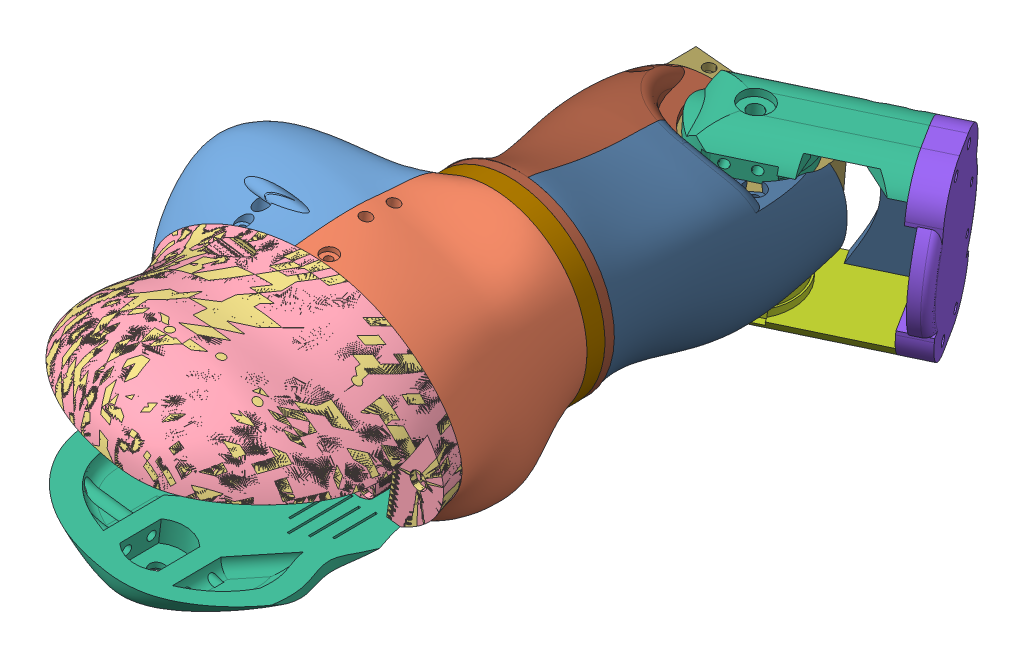
SolidWorks assembly Arm assm L, configuration Default. Lengths in mm.
Overall size (230.27 146.6 398.62).
46 component instances, 28 part files, 28 mates.
Components (placement in the parent):
- middle back L-1: middle back L [Default] at (-34.512 -4.9799 -51.8822) x (0.000653 0.010182 -0.999948) z (-0.991812 0.127707 0.000653) size (90.34 121.18 102.39)
- middle front L-1: middle front L [Default] at (-8.2171 -35.7655 -34.8122) x (0.991812 -0.127707 -0.000653) z (0.000653 0.010182 -0.999948) size (140.79 123.83 87.16)
- top left L-1: top left L [Default] at (-11.5779 -3.0702 -34.4815) x (-0.991812 0.127707 0.000653) z (-0.000653 -0.010182 0.999948) size (182.35 104.85 120.87)
- top brace L-1: top brace L [Default] at (-4.1905 -4.9659 57.5088) x (-0.991812 0.127707 0.000653) z (0.127707 0.99176 0.010182) size (182.35 135.45 104.85)
- left glue widget L-1: left glue widget L [Default] at (-22.5419 19.9221 -28.4086) x (0.000653 0.010182 -0.999948) z (-0.127707 -0.99176 -0.010182) size (13 9 6)
- top right L-1: top right L [Default] at (-10.7036 -55.5456 56.9895) x (-0.000653 -0.010182 0.999948) z (-0.127707 -0.99176 -0.010182) size (132 144.11 34.63)
- gearbox screw block 2 L-1: gearbox screw block 2 L [Default] at (-19.3394 -81.2007 -73.094) x (-0.991625 0.129152 0.000668) z (0.129152 0.991572 0.010181) size (26 29.8 14.3)
- gearbox screw block 1 L-1: gearbox screw block 1 L [Default] at (-25.1738 16.2638 -72.07) x (-0.991625 0.129152 0.000668) z (-0.129152 -0.991572 -0.010181) size (10 29.5 20)
- arm rot mount L-1: arm rot mount L [Default] at (-7.003 -25.9074 -124.2157) x (0.996634 -0.081977 -0.000184) z (-0.000653 -0.010182 0.999948) size (66 66 31)
- lower arm assm L-1: lower arm assm L [Default-_flexible1] at (-87.7884 -5.6779 -95.3829) x (-0.975088 -0.221816 -0.00126) z (0.001292 -0.000001 -0.999999) size (140.99 140.61 148.59) (flexible)
  - arm lower bottom L-1: arm lower bottom L [Default] at (-74.4796 -36.9206 33.9299) x (-0.948607 -0.316453 0.001636) z (-0.001636 0.010071 0.999948) size (61.83 109.64 120.63)
  - arm lower top L-1: arm lower top L [Default] at (-74.4796 -36.9206 33.9299) x (-0.948607 -0.316453 0.001636) z (-0.001636 0.010071 0.999948) size (102.83 109.64 125.02)
  - Mirrorgearbox1-1: Mirrorgearbox1 [Default] at (-78.0538 -48.6826 38.5385) x (0.948607 0.316453 -0.001636) z (0.001636 -0.010071 -0.999948) size (90.22 74 134.56)
    - Mirrorservo gearbox-1: Mirrorservo gearbox [Default] at (7.4002 -24.2748 -89.7718) x (1 0 0) z (0 -1 0) size (87.5 78 20)
    - wormscrew-1: wormscrew [Default] at (21.4002 -4.2748 -75.7718) x (-0.47589 -0.879505 0) z (0 0 -1) size (40 40 51)
    - driveshaft cog-1: driveshaft cog [Default] at (-6.5998 -9.2748 -103.2718) x (0.623441 0 -0.78187) z (0 1 0) size (49.29 49.31 47)
    - Mirrorgearbox top-1: Mirrorgearbox top [Default] at (-6.5998 15.7252 -103.2718) x (-1 0 0) z (0 1 0) size (87.5 78 40)
    - HS-805BB-1: HS-805BB [Default] at (2.9002 -19.2748 -28.6693) x (1 0 0) z (0 1 0) size (83 68.8 30)
    - 608ZZ-1: 608ZZ [Default] at (21.4002 -4.2748 -127.5718) x (0.996867 0.079098 0) z (0 0 1) size (22 22 7)
    - 6806 30x42x7-1: 6806 30x42x7 [Default] at (-6.5998 -22.2748 -103.2718) x (0.979879 0 -0.199591) z (0 1 0) size (42 42 7)
    - 6806 30x42x7-2: 6806 30x42x7 [Default] at (-6.5998 9.7252 -103.2718) x (0.968497 0 -0.249026) z (0 -1 0) size (42 42 7)
    - Mirrorbottom plate pot holder-1: Mirrorbottom plate pot holder [Default] at (-6.5998 15.7252 -103.2718) x (0 0 1) z (0 -1 0) size (50 60 10)
    - cog brace-1: cog brace [Default] at (18.6002 9.7252 -104.6718) x (1 0 0) z (0 -1 0) size (8.5 22.65 3)
    - pot cog-1: pot cog [Default] at (18.6002 12.7252 -97.7718) x (0.51355 0 -0.85806) z (0 -1 0) size (28 27.88 7.9)
    - driveshaft-1: driveshaft [Default] at (-6.5998 -9.2748 -103.2718) x (-0.623441 0 0.78187) z (0 -1 0) size (36.44 35.48 27)
    - Pan Head Cross Recess Screw_ISO-1: Pan Head Cross Recess Screw_ISO [ISO 7045 - M3 x 10 - Z --- 10N] at (-26.5998 23.1252 -103.2718) x (0 -1 0) z (0 0 -1) size (12.35 5.6 5.6)
    - Pan Head Cross Recess Screw_ISO-2: Pan Head Cross Recess Screw_ISO [ISO 7045 - M3 x 10 - Z --- 10N] at (-6.5998 23.1252 -123.2718) x (0 -1 0) z (0.495758 0 -0.868461) size (12.35 5.6 5.6)
    - Pan Head Cross Recess Screw_ISO-3: Pan Head Cross Recess Screw_ISO [ISO 7045 - M3 x 10 - Z --- 10N] at (-6.5998 23.1252 -83.2718) x (0 -1 0) z (0.927545 0 -0.373711) size (12.35 5.6 5.6)
    - Pan Head Cross Recess Screw_ISO-4: Pan Head Cross Recess Screw_ISO [ISO 7045 - M5 x 12 - Z --- 12N] at (-34.5998 -13.2748 -42.0718) x (0 0 -1) z (-1 0 0) size (15.63 9.5 9.5)
    - Pan Head Cross Recess Screw_ISO-5: Pan Head Cross Recess Screw_ISO [ISO 7045 - M5 x 12 - Z --- 12N] at (-34.5998 4.7252 -42.0718) x (0 0 -1) z (-1 0 0) size (15.63 9.5 9.5)
    - Pan Head Cross Recess Screw_ISO-6: Pan Head Cross Recess Screw_ISO [ISO 7045 - M3 x 30 - Z --- 25N] at (-27.0895 14.1252 -123.7718) x (0 -1 0) z (0 0 -1) size (32.35 5.6 5.6)
    - Pan Head Cross Recess Screw_ISO-7: Pan Head Cross Recess Screw_ISO [ISO 7045 - M3 x 30 - Z --- 25N] at (-18.0998 -22.6748 -69.7718) x (0 1 0) z (0 0 -1) size (32.35 5.6 5.6)
    - Pan Head Cross Recess Screw_ISO-8: Pan Head Cross Recess Screw_ISO [ISO 7045 - M3 x 30 - Z --- 25N] at (34.9002 14.1252 -82.7718) x (0 -1 0) z (-0.8218 0 -0.569776) size (32.35 5.6 5.6)
    - Pan Head Cross Recess Screw_ISO-9: Pan Head Cross Recess Screw_ISO [ISO 7045 - M3 x 30 - Z --- 25N] at (-5.5998 14.1252 -71.7718) x (0 -1 0) z (0.38373 0 -0.923445) size (32.35 5.6 5.6)
    - Pan Head Cross Recess Screw_ISO-10: Pan Head Cross Recess Screw_ISO [ISO 7045 - M2 x 6 - Z --- 6N] at (18.6002 6.6252 -115.2718) x (0 1 0) z (0.855583 0 0.517665) size (7.57 4 4)
    - Pan Head Cross Recess Screw_ISO-11: Pan Head Cross Recess Screw_ISO [ISO 7045 - M3 x 5 - Z --- 5N] at (-19.8916 -13.6748 -113.8703) x (0 1 0) z (0.934817 0 -0.355129) size (7.35 5.6 5.6)
    - Pan Head Cross Recess Screw_ISO-12: Pan Head Cross Recess Screw_ISO [ISO 7045 - M3 x 5 - Z --- 5N] at (9.2246 -13.6748 -109.4836) x (0 1 0) z (-0.000145 0 -1) size (7.35 5.6 5.6)
    - Pan Head Cross Recess Screw_ISO-13: Pan Head Cross Recess Screw_ISO [ISO 7045 - M3 x 5 - Z --- 5N] at (-9.1325 -13.6748 -86.4615) x (0 1 0) z (-0.12044 0 -0.992721) size (7.35 5.6 5.6)
    - Pan Head Cross Recess Screw_ISO-14: Pan Head Cross Recess Screw_ISO [ISO 7045 - M3 x 30 - Z --- 25N] at (36.9002 14.1252 -123.7718) x (0 -1 0) z (0.993717 0 0.111922) size (32.35 5.6 5.6)
    - Pan Head Cross Recess Screw_ISO-15: Pan Head Cross Recess Screw_ISO [ISO 7045 - M5 x 12 - Z --- 12N] at (40.4002 4.7252 -42.0718) x (0 0 -1) z (0.445798 -0.895134 0) size (15.63 9.5 9.5)
    - Pan Head Cross Recess Screw_ISO-16: Pan Head Cross Recess Screw_ISO [ISO 7045 - M5 x 12 - Z --- 12N] at (40.4002 -13.2748 -42.0718) x (0 0 -1) z (0.583619 -0.812027 0) size (15.63 9.5 9.5)
- elbow left L-1: elbow left L [Default] at (10.3466 10.6184 -236.6059) x (0.849736 -0.07847 -0.521335) z (-0.098152 -0.995119 -0.010197) size (91.97 52.06 22)
- elbow right L-1: elbow right L [Default] at (1.0222 -83.9179 -237.5746) x (-0.849736 0.07847 0.521335) z (0.098152 0.995119 0.010197) size (91.97 52.06 22)
- elbow bottom L-1: elbow bottom L [Default] at (73.5803 -42.9178 -278.9339) x (0.098152 0.995119 0.010197) z (-0.849736 0.07847 0.521335) size (95 77.15 15.7)
- ring cover-1: ring cover [Default] at (-7.003 -25.9074 -124.2157) x (1 -0.000003 0.000653) z (-0.000653 -0.010182 0.999948) size (100 100 9.5)
- ELBOW BRACE-1: ELBOW BRACE [Default] at (37.6462 -49.5787 -286.9269) x (-0.098152 -0.995119 -0.010197) z (0.517991 -0.059835 0.853291) size (71 35 8)
Mates (geometry in assembly coordinates):
- Coincident1: coincident anti-aligned: plane of middle back L-1 through (-38.0759 -33.5634 125.199) normal (0.991812 -0.127707 -0.000653); plane of middle front L-1 through (-38.0759 -33.5634 125.199) normal (-0.991812 0.127707 0.000653)
- Coincident2: coincident aligned: plane of middle back L-1 through (-8.1649 -34.9509 -114.8081) normal (0.000653 0.010182 -0.999948); plane of middle front L-1 through (-8.1649 -34.9509 -114.8081) normal (0.000653 0.010182 -0.999948)
- Coincident3: coincident anti-aligned: plane of middle back L-1 through (-8.2171 -35.7655 -34.8122) normal (-0.000653 -0.010182 0.999948); plane of top left L-1 through (-8.2171 -35.7655 -34.8122) normal (0.000653 0.010182 -0.999948)
- Parallel1: parallel anti-aligned: line of middle front L-1; line of top left L-1
- Coincident4: coincident anti-aligned: plane of top left L-1 through (-14.0599 12.7997 -30.3213) normal (0.000653 0.010182 -0.999948); plane of left glue widget L-1 through (-14.5558 12.8635 -30.321) normal (-0.000653 -0.010182 0.999948)
- Coincident5: coincident anti-aligned: plane of top left L-1 through (-13.2936 18.7502 -30.2602) normal (-0.127707 -0.99176 -0.010182); plane of left glue widget L-1 through (-22.7074 20.0958 -43.2534) normal (0.127707 0.99176 0.010182)
- Distance1: distance = 0.5 mm anti-aligned: plane of left glue widget L-1 through (-23.4736 14.1453 -43.3145) normal (-0.991812 0.127707 0.000653); plane of top left L-1 through (-23.2118 20.0273 -30.2537) normal (0.991812 -0.127707 -0.000653)
- Coincident6: coincident anti-aligned: plane of middle front L-1 through (-8.2171 -35.7655 -34.8122) normal (-0.000653 -0.010182 0.999948); plane of top right L-1 through (-8.2171 -35.7655 -34.8122) normal (0.000653 0.010182 -0.999948)
- Coincident7: coincident anti-aligned: plane of top left L-1 through (-10.748 -56.238 124.986) normal (-0.127707 -0.99176 -0.010182); plane of top right L-1 through (65.125 -65.7064 95.6079) normal (0.127707 0.99176 0.010182)
- Coincident8: coincident: point of top left L-1; point of top right L-1
- Coincident9: coincident: point of middle back L-1; point of middle front L-1
- Coincident10: coincident anti-aligned: plane of middle back L-1 through (-8.2171 -35.7655 -34.8122) normal (-0.000653 -0.010182 0.999948); plane of top left L-1 through (-8.2171 -35.7655 -34.8122) normal (0.000653 0.010182 -0.999948)
- Coincident11: coincident: point of middle back L-1; point of top left L-1
- Concentric5: concentric aligned: cylinder of middle front L-1; cylinder of arm rot mount L-1
- Coincident12: coincident anti-aligned: circle of arm rot mount L-1; circle of ?
- Coincident13: coincident anti-aligned: circle of arm rot mount L-1; circle of ?
- Coincident17: coincident anti-aligned: circle of elbow left L-1; circle of elbow bottom L-1
- Coincident18: coincident anti-aligned: circle of elbow left L-1; circle of elbow bottom L-1
- Coincident19: coincident anti-aligned: circle of elbow right L-1; circle of elbow bottom L-1
- Coincident20: coincident anti-aligned: circle of elbow right L-1; circle of elbow bottom L-1
- Concentric6: concentric aligned: cylinder of ?; circle of ?
- Concentric7: concentric aligned: cylinder of middle front L-1; cylinder of arm rot mount L-1
- Coincident25: coincident anti-aligned: plane of lower arm assm L-1/Mirrorgearbox1-1/Mirrorservo gearbox-1 through (35.5711 -13.7138 -262.3385) normal (0.098152 0.995119 0.010197); plane of elbow left L-1 through (-3.3888 -10.5276 -198.2662) normal (-0.098152 -0.995119 -0.010197)
- Concentric9: concentric aligned: cylinder of lower arm assm L-1/Mirrorgearbox1-1/driveshaft-1; cylinder of elbow left L-1
- Coincident26: coincident anti-aligned: circle of ?; circle of ring cover-1
- Coincident27: coincident aligned: circle of elbow bottom L-1; circle of ELBOW BRACE-1
- Concentric10: concentric aligned: circle of elbow left L-1; circle of ELBOW BRACE-1
- Coincident29: coincident anti-aligned: plane of middle front L-1 through (-8.1649 -34.9509 -114.8081) normal (0.000653 0.010182 -0.999948); circle of ring cover-1
